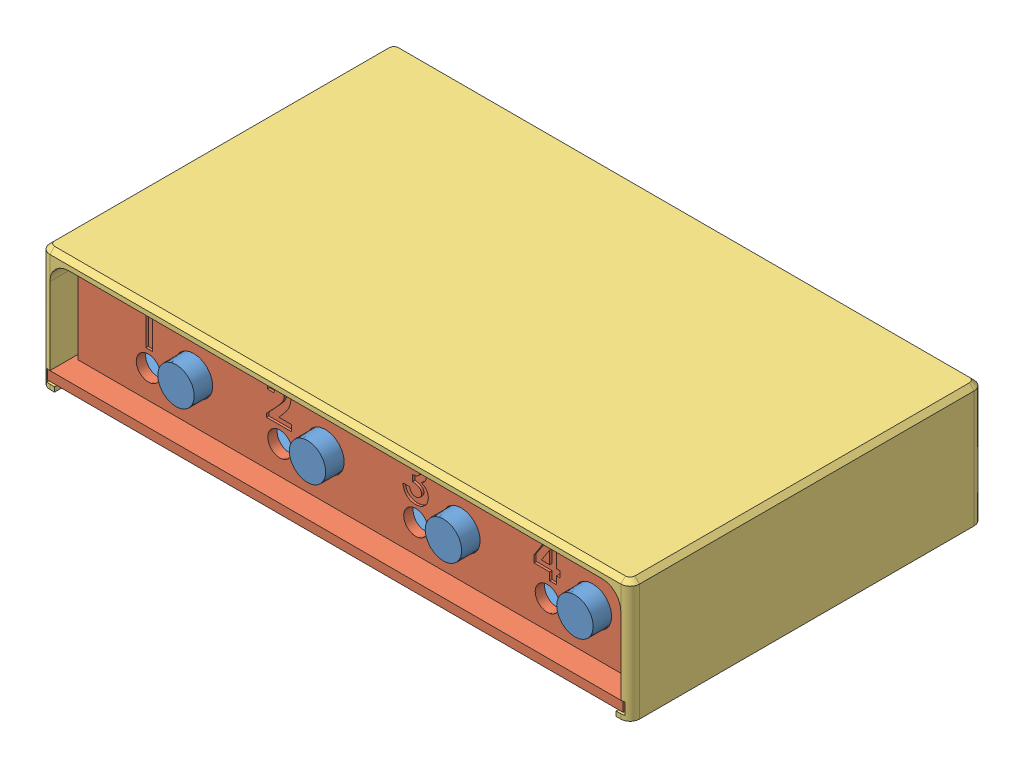
SolidWorks assembly asm, configuration Défaut. Lengths in mm.
Overall size (126 26 78.05).
3 component instances, 3 part files, 6 mates.
Components (placement in the parent):
- pcb-1: pcb [Défaut] at (-1.1279 4.0601 114.45) size (114.45 18 76.85)
- bas-1: bas [Défaut] at (-1.2029 0.4601 117.175) x (1 0 0) z (0 1 0) size (123 74 22)
- haut-1: haut [Défaut] at (-1.2029 24.9601 116.425) x (-1 0 0) z (0 0 1) size (126 26 75.5)
Mates (geometry in assembly coordinates):
- Coaxiale1: concentric anti-aligned: cylinder of pcb-1 through (48.7971 11.9601 152.975) axis (0 0 -1) radius 3.9; cylinder of bas-1 through (48.7971 11.9601 80.175) axis (0 0 1) radius 4.05
- Coïncidente1: coincident anti-aligned: plane of pcb-1 through (-58.3529 5.6601 147.175) normal (0 0 1); plane of bas-1 through (58.7971 22.4601 147.175) normal (0 0 -1)
- Coïncidente2: coincident anti-aligned: plane of bas-1 through (-1.2029 2.4601 117.175) normal (0 1 0); plane of haut-1 through (-1.2029 2.4601 116.425) normal (0 -1 0)
- Coaxiale2: concentric anti-aligned: cylinder of pcb-1 through (-36.4529 11.9601 152.975) axis (0 0 -1) radius 3.9; cylinder of bas-1 through (-36.4529 11.9601 80.175) axis (0 0 1) radius 4.05
- Coïncidente4: coincident anti-aligned: plane of bas-1 through (58.7971 22.4601 147.175) normal (0 0 -1); plane of haut-1 through (51.7971 15.9601 147.175) normal (0 0 1)
- Coaxiale3: concentric anti-aligned: cylinder of pcb-1 through (45.9471 11.9601 76.125) axis (0 0 1) radius 3.9; circle of haut-1
